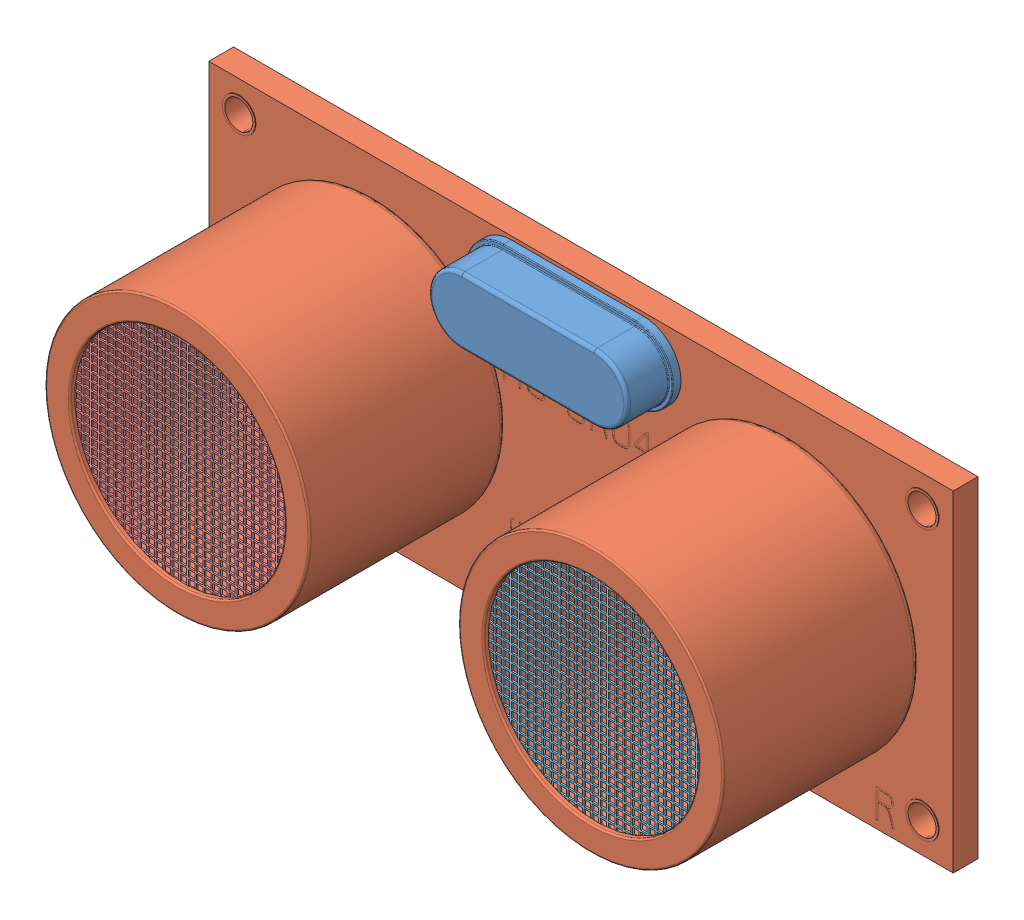
SolidWorks assembly hc-sr04, configuration Default. Lengths in mm.
Overall size (45 25.83 17.8).
6 component instances, 5 part files, 0 mates.
Components (placement in the parent):
- hc-sr04.step-1: hc-sr04.step [Default] at origin size (45 25.83 17.8)
  - Quarz.step-1: Quarz.step [Default] at origin size (12.5 4.5 5.2)
  - Platine.step-1: Platine.step [Default] at origin size (45 20 14.3)
  - Pins_4fach_90Grad_001.step-1: Pins_4fach_90Grad_001.step [Default] at (3.81 -8.65 2.9) x (0 -1 0) z (0 0 -1) size (8.45 10.16 7.3)
  - HC_SR04_gitter_001.step-1: HC_SR04_gitter_001.step [Default] at origin size (14.85 14.85 0.1)
  - HC_SR04_gitter_002.step-1: HC_SR04_gitter_002.step [Default] x (-1 0 0) z (0 0 1) size (14.85 14.85 0.1)
